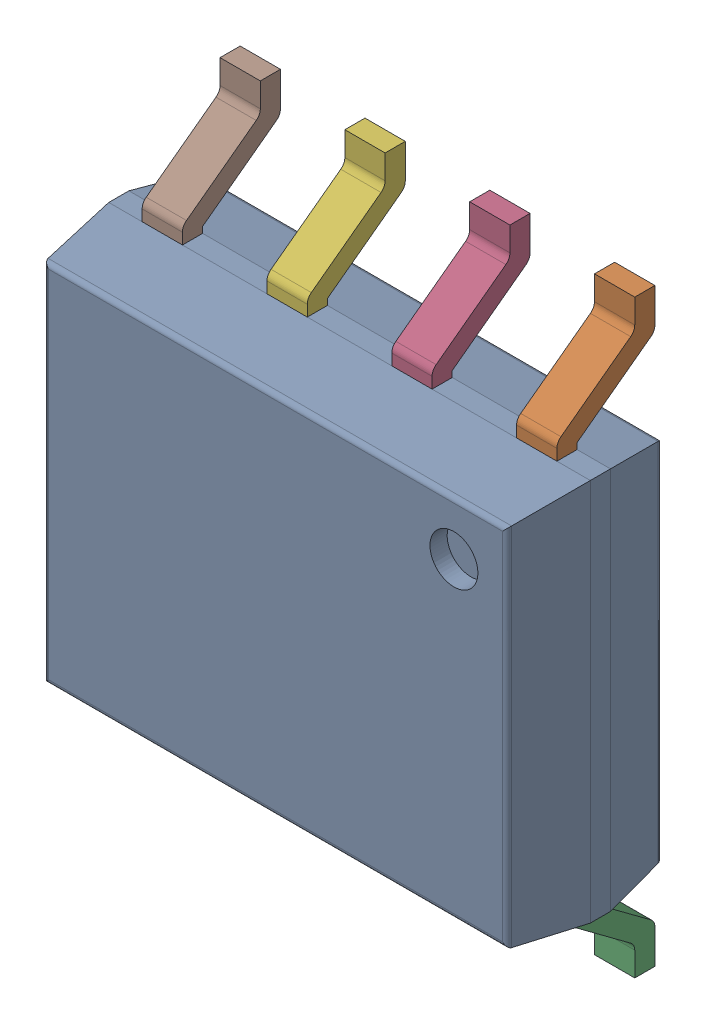
SolidWorks assembly IC7_1.step, configuration Default. Lengths in mm.
Overall size (4.9 6 1.75).
3 component instances, 2 part files, 0 mates.
Components (placement in the parent):
- 6348793408_1.step-3: 6348793408_1.step [Default] at (432.06 250.881 0) x (0 -1 0) z (0 0 1) size (6 4.9 1.75)
  - Body-1216_1.step-5: Body-1216_1.step [Default] at origin size (3.9 4.9 1.57)
  - PinsArrayLR-1217_1.step-5: PinsArrayLR-1217_1.step [Default] at origin size (6 4.22 1)
